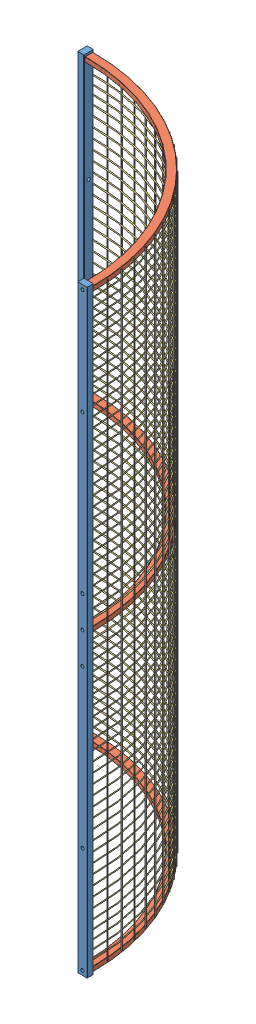
SolidWorks assembly W32R90-190-Axelent, configuration Default. Lengths in mm.
Overall size (664 1900 664).
7 component instances, 3 part files, 0 mates.
Components (placement in the parent):
- 02Rxx-xxx_Ram(02R90-190)-1-1: 02Rxx-xxx_Ram(02R90-190)-1 [Default] at origin size (664 1900 664)
  - 20x30(1900)-1-1: 20x30(1900)-1 [Default] at origin size (20 1900 30)
  - 20x30(1900)-1-2: 20x30(1900)-1 [Default] at (639 0 639) x (0 0 -1) z (1 0 0) size (20 1900 30)
  - 2515100-R90(2515100-R90)-1: 2515100-R90(2515100-R90) [Default] at (10 -935.5 629) x (0 0 1) z (-1 0 0) size (643 15 643)
  - 2515100-R90(2515100-R90)-2: 2515100-R90(2515100-R90) [Default] at (10 0 629) x (0 0 1) z (-1 0 0) size (643 15 643)
  - 2515100-R90(2515100-R90)-3: 2515100-R90(2515100-R90) [Default] at (10 935.5 629) x (0 0 1) z (-1 0 0) size (643 15 643)
- 02R90-xxx_Nät(90-190)-1-1: 02R90-xxx_Nät(90-190)-1 [Default] at (10 0 629) x (0 0 1) z (-1 0 0) size (651.82 1875 651.82)
